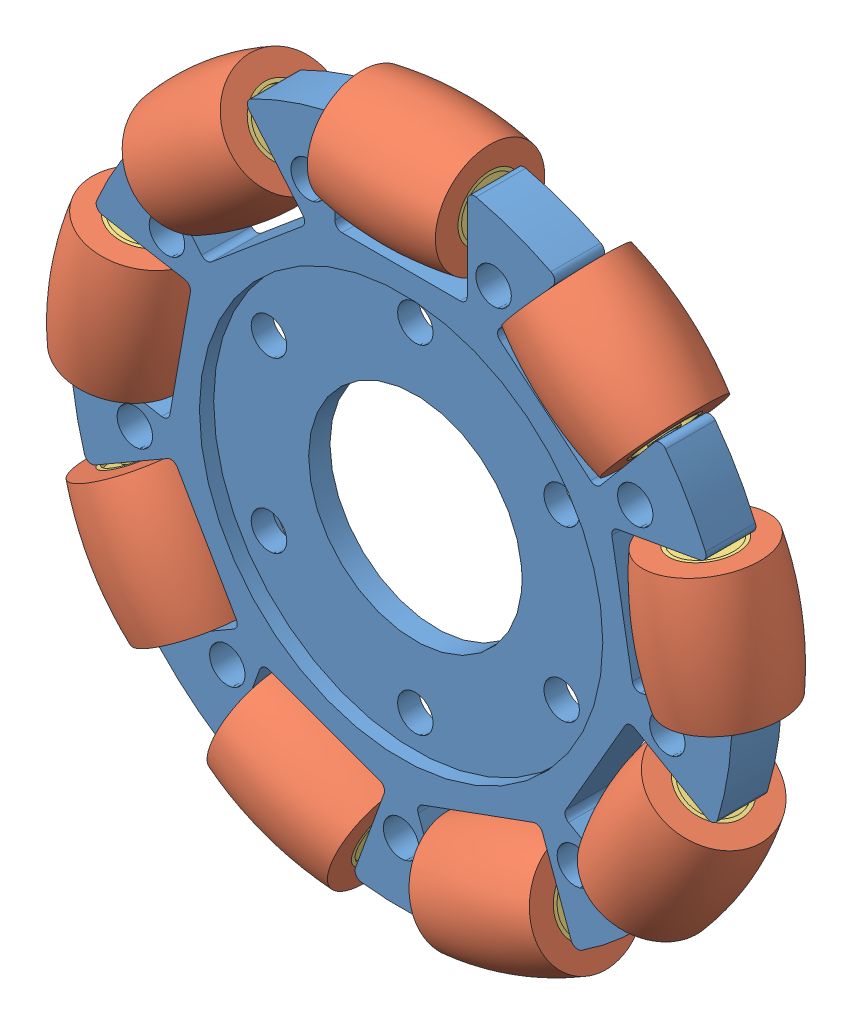
SolidWorks assembly Single Side, configuration Default. Lengths in mm.
Overall size (107.72 106.08 23.21).
28 component instances, 3 part files, 4 mates.
Components (placement in the parent):
- Frame-1: Frame [Default] at origin size (92.88 91.83 7)
- Roller_New-1: Roller_New [預設] at (0 41.5 0) x (1 0 0) z (0 -0.498092 0.867124) size (18 17 17)
- MR93zz_3x9x4mm-1: MR93zz_3x9x4mm [預設] at (7 41.5 0) x (0 0 -1) z (1 0 0) size (9 9 4)
- MR93zz_3x9x4mm-2: MR93zz_3x9x4mm [預設] at (-7 41.5 0) x (0 0 1) z (-1 0 0) size (9 9 4)
- Roller_New-2: Roller_New [預設] at (-26.6757 31.7908 0) x (0.766044 0.642788 0) z (0.320168 -0.381561 0.867124) size (18 17 17)
- Roller_New-3: Roller_New [預設] at (-40.8695 7.2064 0) x (0.173648 0.984808 0) z (0.490525 -0.086493 0.867124) size (18 17 17)
- Roller_New-4: Roller_New [預設] at (-35.9401 -20.75 0) x (-0.5 0.866025 0) z (0.431361 0.249046 0.867124) size (18 17 17)
- Roller_New-5: Roller_New [預設] at (-14.1938 -38.9972 0) x (-0.939693 0.34202 0) z (0.170358 0.468054 0.867124) size (18 17 17)
- Roller_New-6: Roller_New [預設] at (14.1938 -38.9972 0) x (-0.939693 -0.34202 0) z (-0.170358 0.468054 0.867124) size (18 17 17)
- Roller_New-7: Roller_New [預設] at (35.9401 -20.75 0) x (-0.5 -0.866025 0) z (-0.431361 0.249046 0.867124) size (18 17 17)
- Roller_New-8: Roller_New [預設] at (40.8695 7.2064 0) x (0.173648 -0.984808 0) z (-0.490525 -0.086493 0.867124) size (18 17 17)
- Roller_New-9: Roller_New [預設] at (26.6757 31.7908 0) x (0.766044 -0.642788 0) z (-0.320168 -0.381561 0.867124) size (18 17 17)
- MR93zz_3x9x4mm-3: MR93zz_3x9x4mm [預設] at (-32.038 27.2913 0) x (0 0 1) z (-0.766044 -0.642788 0) size (9 9 4)
- MR93zz_3x9x4mm-4: MR93zz_3x9x4mm [預設] at (-42.0851 0.3127 0) x (0 0 1) z (-0.173648 -0.984808 0) size (9 9 4)
- MR93zz_3x9x4mm-5: MR93zz_3x9x4mm [預設] at (-32.4401 -26.8122 0) x (0 0 1) z (0.5 -0.866025 0) size (9 9 4)
- MR93zz_3x9x4mm-6: MR93zz_3x9x4mm [預設] at (-7.616 -41.3914 0) x (0 0 1) z (0.939693 -0.34202 0) size (9 9 4)
- MR93zz_3x9x4mm-7: MR93zz_3x9x4mm [預設] at (20.7717 -36.6031 0) x (0 0 1) z (0.939693 0.34202 0) size (9 9 4)
- MR93zz_3x9x4mm-8: MR93zz_3x9x4mm [預設] at (39.4401 -14.6878 0) x (0 0 1) z (0.5 0.866025 0) size (9 9 4)
- MR93zz_3x9x4mm-9: MR93zz_3x9x4mm [預設] at (39.654 14.1001 0) x (0 0 1) z (-0.173648 0.984808 0) size (9 9 4)
- MR93zz_3x9x4mm-10: MR93zz_3x9x4mm [預設] at (21.3134 36.2904 0) x (0 0 1) z (-0.766044 0.642788 0) size (9 9 4)
- MR93zz_3x9x4mm-11: MR93zz_3x9x4mm [預設] at (-21.3134 36.2904 0) x (0 0 -1) z (0.766044 0.642788 0) size (9 9 4)
- MR93zz_3x9x4mm-12: MR93zz_3x9x4mm [預設] at (-39.654 14.1001 0) x (0 0 -1) z (0.173648 0.984808 0) size (9 9 4)
- MR93zz_3x9x4mm-13: MR93zz_3x9x4mm [預設] at (-39.4401 -14.6878 0) x (0 0 -1) z (-0.5 0.866025 0) size (9 9 4)
- MR93zz_3x9x4mm-14: MR93zz_3x9x4mm [預設] at (-20.7717 -36.6031 0) x (0 0 -1) z (-0.939693 0.34202 0) size (9 9 4)
- MR93zz_3x9x4mm-15: MR93zz_3x9x4mm [預設] at (7.616 -41.3914 0) x (0 0 -1) z (-0.939693 -0.34202 0) size (9 9 4)
- MR93zz_3x9x4mm-16: MR93zz_3x9x4mm [預設] at (32.4401 -26.8122 0) x (0 0 -1) z (-0.5 -0.866025 0) size (9 9 4)
- MR93zz_3x9x4mm-17: MR93zz_3x9x4mm [預設] at (42.0851 0.3127 0) x (0 0 -1) z (0.173648 -0.984808 0) size (9 9 4)
- MR93zz_3x9x4mm-18: MR93zz_3x9x4mm [預設] at (32.038 27.2913 0) x (0 0 -1) z (0.766044 -0.642788 0) size (9 9 4)
Mates (geometry in assembly coordinates):
- 重合/共線/共點1: coincident: circle of Roller_New-1; circle of MR93zz_3x9x4mm-1
- 同軸心1: concentric: cylinder of Frame-1 through (-9.2 41.5 0) axis (1 0 0) radius 1.5; cylinder of Roller_New-1 through (-9 41.5 0) axis (1 0 0) radius 2.5
- 寬度1: width: plane of Frame-1 through (9.3 44.3225 3.5) normal (-1 0 0); plane of Frame-1 through (-9.3 32.5376 3.5) normal (1 0 0); plane of Roller_New-1 through (9 41.5 0) normal (1 0 0); plane of Roller_New-1 through (-9 41.5 0) normal (-1 0 0)
- 重合/共線/共點2: coordinate: point of Frame-1; point of assembly
